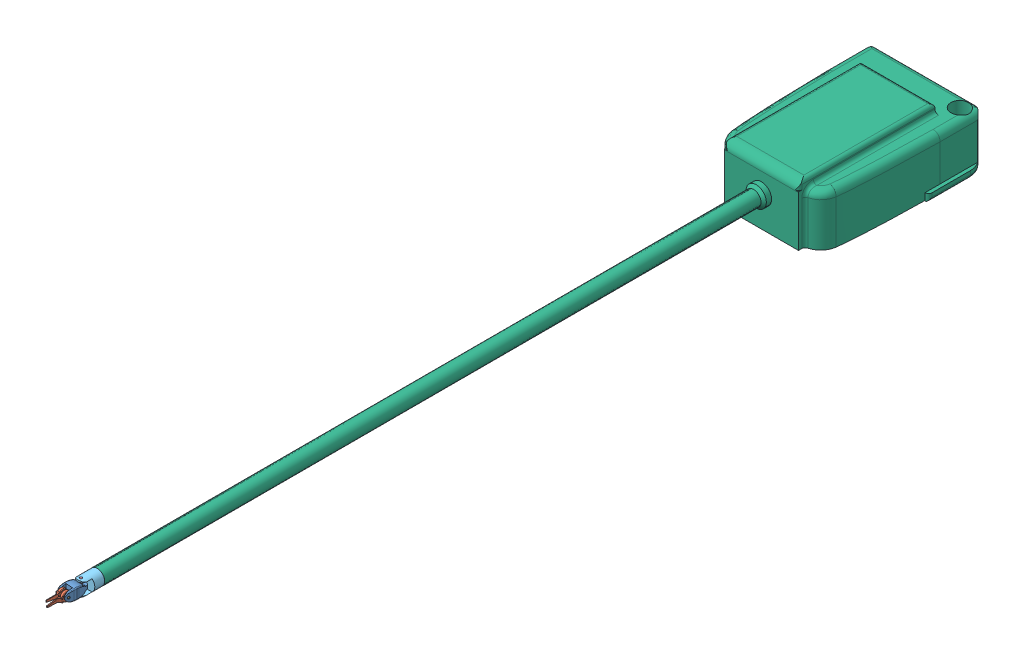
SolidWorks assembly Potts_Scissors, configuration Default. Lengths in mm.
Overall size (68.49 33 491.79).
7 component instances, 6 part files, 12 mates.
Components (placement in the parent):
- Tool_Wristis_Potts_Scissors_Link_2-1: Tool_Wristis_Potts_Scissors_Link_2 [Default] at (60.6924 21.5109 299.2499) x (0.058926 0 -0.998262) z (0.998262 0 0.058926) size (13.22 7.35 6.88)
- Tool_Wristis_Potts_scissors_Link_3-1: Tool_Wristis_Potts_scissors_Link_3 [Default] at (63.9125 21.5109 303.2466) x (-0.012031 0.978935 0.203817) z (0.998262 0 0.058926) size (5 11.9 1.98)
- Tool_Wristis_Potts_scissors_Link_3-2: Tool_Wristis_Potts_scissors_Link_3 [Default] at (63.3136 21.5109 303.2112) x (-0.008619 -0.989246 0.146009) z (-0.998262 0 -0.058926) size (5 11.9 1.98)
- Tool_Wristis_Potts_Scissors_shaft_Link_2_3-1: Tool_Wristis_Potts_Scissors_shaft_Link_2_3 [Default] at (61.1673 21.5109 303.0845) x (0.058926 0 -0.998262) z (0.998262 0 0.058926) size (1.3 1.3 5)
- Tool_Wrists_Shaft_Link_1_2-1: Tool_Wrists_Shaft_Link_1_2 [Default] at (64.1874 17.3109 294.3473) x (1 0 0) z (0 1 0) size (1.3 1.3 8.02)
- Tool_Wrists_Link_1-1: Tool_Wrists_Link_1 [Default] at (64.1874 21.3109 285.2473) x (0 1 0) z (0 0 1) size (8.32 8.32 11)
- Tool_main-1: Tool_main [Default] at (64.1874 21.3109 -81.5527) size (68.49 33 464)
Mates (geometry in assembly coordinates):
- Concentric1: concentric anti-aligned: circle of Tool_Wristis_Potts_Scissors_Link_2-1; cylinder of Tool_Wristis_Potts_Scissors_shaft_Link_2_3-1
- Distance1: distance = 4.5 mm aligned: plane of Tool_Wristis_Potts_Scissors_shaft_Link_2_3-1 through (66.1586 21.5109 303.3791) normal (0.998262 0 0.058926); plane of Tool_Wristis_Potts_Scissors_Link_2-1 through (61.5368 17.8355 305.3101) normal (0.998262 0 0.058926)
- Concentric2: concentric anti-aligned: cylinder of Tool_Wristis_Potts_scissors_Link_3-1; cylinder of Tool_Wristis_Potts_Scissors_shaft_Link_2_3-1
- Coincident3: coincident anti-aligned: plane of Tool_Wristis_Potts_Scissors_Link_2-1 through (65.43 17.8355 305.54) normal (-0.998262 0 -0.058926); plane of Tool_Wristis_Potts_scissors_Link_3-1 through (65.5597 21.5109 303.3438) normal (0.998262 0 0.058926)
- Coincident4: coincident anti-aligned: plane of Tool_Wristis_Potts_scissors_Link_3-2 through (61.6664 21.5109 303.114) normal (-0.998262 0 -0.058926); plane of Tool_Wristis_Potts_Scissors_Link_2-1 through (61.5368 17.8355 305.3101) normal (0.998262 0 0.058926)
- Concentric3: concentric aligned: circle of Tool_Wristis_Potts_scissors_Link_3-2; cylinder of Tool_Wristis_Potts_Scissors_shaft_Link_2_3-1
- Concentric6: concentric anti-aligned: cylinder of Tool_Wristis_Potts_Scissors_Link_2-1; cylinder of Tool_Wrists_Shaft_Link_1_2-1
- Concentric7: concentric anti-aligned: cylinder of Tool_Wrists_Shaft_Link_1_2-1; cylinder of Tool_Wrists_Link_1-1
- Distance2: distance = 2 mm anti-aligned: plane of Tool_Wristis_Potts_Scissors_Link_2-1 through (67.4234 22.5109 292.1341) normal (0 1 0); plane of Tool_Wrists_Link_1-1 through (68.3474 24.5109 297.1047) normal (0 -1 0)
- Distance3: distance = 7.2 mm aligned: plane of Tool_Wrists_Shaft_Link_1_2-1 through (64.1874 17.3109 294.3473) normal (0 -1 0); plane of Tool_Wrists_Link_1-1 through (68.3474 24.5109 297.1047) normal (0 -1 0)
- Coincident8: coincident anti-aligned: plane of Tool_Wrists_Link_1-1 through (64.1874 21.3109 285.2473) normal (0 0 -1); plane of Tool_main-1 through (64.1874 21.3109 285.2473) normal (0 0 1)
- Concentric9: concentric aligned: circle of Tool_Wrists_Link_1-1; circle of Tool_main-1
